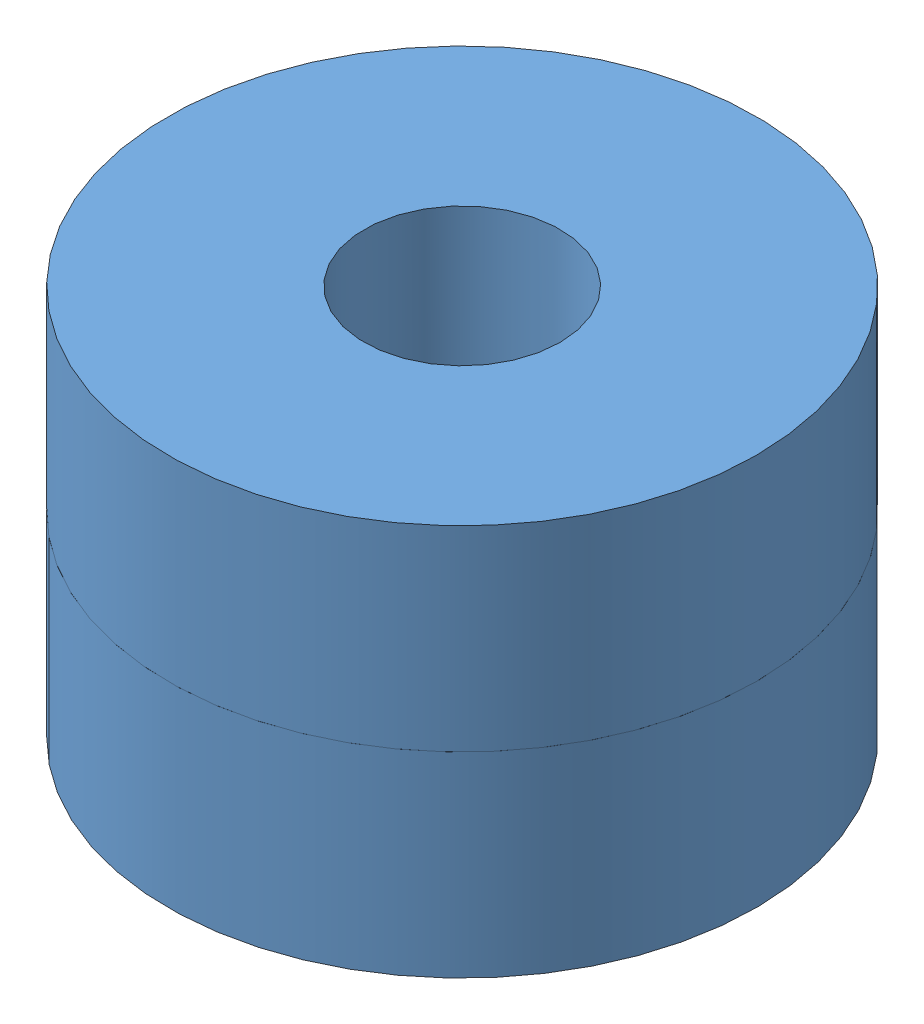
SolidWorks assembly lens, configuration Default. Lengths in mm.
Overall size (53.23 25.4 53.23).
3 component instances, 2 part files, 3 mates.
Components (placement in the parent):
- Half-1: Half [Default] at (-9.6268 5.3886 -0.2729) size (38.1 12.7 38.1)
- Half-2: Half [Default] at (-9.6268 5.3906 -0.2729) x (0.58898 0 0.808148) z (0.808148 0 -0.58898) size (38.1 12.7 38.1)
- Conductor-1: Conductor [Default] at (-9.6268 5.4195 -0.2729) x (-0.519372 0 0.854548) z (-0.854548 0 -0.519372) size (29.21 19.53 29.21)
Mates (geometry in assembly coordinates):
- Concentric2: concentric anti-aligned: cylinder of Half-1 through (-9.6268 -13.8762 -0.2729) axis (0 -1 0) radius 6.35; cylinder of Half-2 through (-9.6268 24.6555 -0.2729) axis (0 1 0) radius 6.35
- Coincident9: coincident anti-aligned: plane of Half-1 through (-27.0893 5.3896 -0.2729) normal (0 -1 0); plane of Half-2 through (-19.9119 5.3896 -14.3852) normal (0 1 0)
- Concentric7: concentric anti-aligned: circle of Half-1; line of Conductor-1 through (-9.6268 -2.4058 -0.2729) axis (0 1 0)
